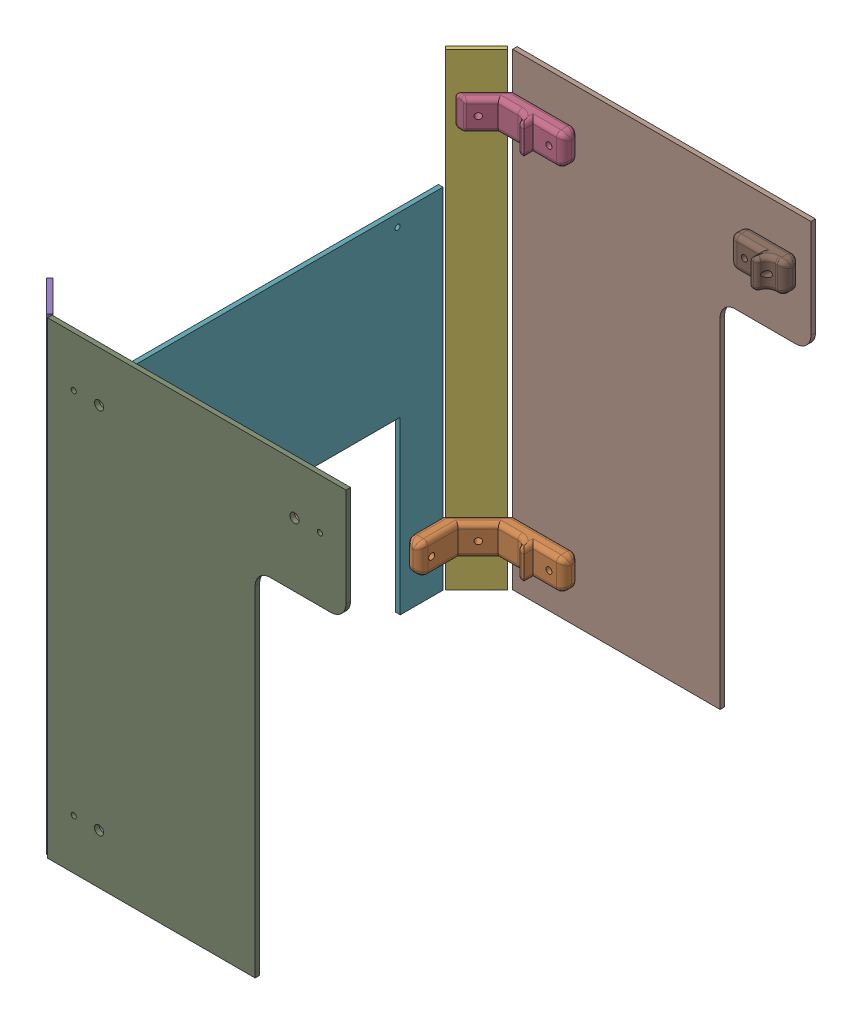
SolidWorks assembly Assemblage_Plexi, configuration Défaut. Lengths in mm.
Overall size (222.7 309 310).
11 component instances, 6 part files, 29 mates.
Components (placement in the parent):
- Support_Plexi-1: Support_Plexi [Défaut] at (-28.5354 258.1684 1538.5415) size (66.7 20 48.2)
- Support_Plexi-2: Support_Plexi [Défaut] at (-28.5354 258.1684 1254.5415) x (1 0 0) z (0 0 -1) size (66.7 20 48.2)
- Support_Plexi_2-1: Support_Plexi_2 [Défaut] at (-28.5354 501.1684 1538.5415) size (61.67 20 21)
- Support_Plexi_2-2: Support_Plexi_2 [Défaut] at (-28.5354 501.1684 1254.5415) x (1 0 0) z (0 0 -1) size (61.67 20 21)
- Plexi_Angle_V2-1: Plexi_Angle_V2 [Défaut] at (-73.2495 379.6684 1537.3274) x (0.707107 0 0.707107) z (-0.707107 0 0.707107) size (29 309 3)
- Plexi_Angle_V2-2: Plexi_Angle_V2 [Défaut] at (-76.303 379.6684 1254.5665) x (0.707107 0 -0.707107) z (0.707107 0 0.707107) size (29 309 3)
- Plexi_Arrière-1: Plexi_Arrière [Défaut] at (-85.2354 455.6484 1267.7865) x (0 0 1) z (-1 0 0) size (257.51 230.48 3)
- Plexi_Latéral-1: Plexi_Latéral [Défaut] at (35.9646 379.6684 1244.5415) x (-1 0 0) z (0 0 -1) size (197 309 3)
- Plexi_Latéral-2: Plexi_Latéral [Défaut] at (35.9646 379.6684 1551.5415) x (-1 0 0) z (0 0 -1) size (197 309 3)
- Support_Plexi_1-1: Support_Plexi_1 [Défaut] at (100.4646 501.1684 1538.5415) x (-1 0 0) z (0 0 1) size (36.75 20 16)
- Support_Plexi_1-2: Support_Plexi_1 [Défaut] at (100.4646 501.1684 1254.5415) x (-1 0 0) z (0 0 -1) size (36.75 20 16)
Mates (geometry in assembly coordinates):
- Rainure1: slot anti-aligned: cylinder of Support_Plexi-1 through (-27.7844 258.1684 1491.0905) axis (-0.707107 0 0.707107) radius 2; plane of Plexi_Angle_V2-1 through (-77.8457 256.4184 1536.9738) normal (0 1 0); cylinder of Plexi_Angle_V2-1 through (-77.8457 258.1684 1536.9738) axis (0.707107 0 -0.707107) radius 1.75
- Coïncidente1: coincident anti-aligned: plane of Support_Plexi-1 through (-62.0354 248.1684 1548.5415) normal (-0.707107 0 0.707107); plane of Plexi_Angle_V2-1 through (-73.2495 379.6684 1537.3274) normal (0.707107 0 -0.707107)
- Rainure2: slot anti-aligned: cylinder of Support_Plexi_2-1 through (-27.7844 501.1684 1491.0905) axis (-0.707107 0 0.707107) radius 2; plane of Plexi_Angle_V2-1 through (-77.8457 499.4184 1536.9738) normal (0 1 0); cylinder of Plexi_Angle_V2-1 through (-77.8457 501.1684 1536.9738) axis (0.707107 0 -0.707107) radius 1.75
- Coïncidente2: coincident anti-aligned: plane of Support_Plexi_2-1 through (-62.0354 491.1684 1548.5415) normal (-0.707107 0 0.707107); plane of Plexi_Angle_V2-1 through (-73.2495 379.6684 1537.3274) normal (0.707107 0 -0.707107)
- Coïncidente3: coincident aligned: plane of Support_Plexi-2 through (-62.0354 268.1684 1244.5415) normal (-0.707107 0 -0.707107); plane of Support_Plexi_2-2 through (-62.0354 511.1684 1244.5415) normal (-0.707107 0 -0.707107)
- Coïncidente4: coincident anti-aligned: plane of Support_Plexi-2 through (-62.0354 268.1684 1244.5415) normal (-0.707107 0 -0.707107); plane of Plexi_Angle_V2-2 through (-74.1817 379.6684 1256.6878) normal (0.707107 0 0.707107)
- Rainure3: slot aligned: plane of Plexi_Angle_V2-2 through (-76.6566 256.4184 1259.1627) normal (0 1 0); cylinder of Support_Plexi-2 through (-27.7844 258.1684 1301.9925) axis (-0.707107 0 -0.707107) radius 2; cylinder of Plexi_Angle_V2-2 through (-76.6566 258.1684 1259.1627) axis (-0.707107 0 -0.707107) radius 1.75
- Rainure5: slot aligned: cylinder of Support_Plexi_2-2 through (-27.7844 501.1684 1301.9925) axis (-0.707107 0 -0.707107) radius 2; plane of Plexi_Angle_V2-2 through (-76.6566 499.4184 1259.1627) normal (0 1 0); cylinder of Plexi_Angle_V2-2 through (-76.6566 501.1684 1259.1627) axis (-0.707107 0 -0.707107) radius 1.75
- Coïncidente5: coincident aligned: plane of Support_Plexi-1 through (-18.5354 268.1684 1541.5415) normal (0 1 0); plane of Support_Plexi-2 through (-18.5354 268.1684 1251.5415) normal (0 1 0)
- Coïncidente6: coincident aligned: plane of Support_Plexi-1 through (-85.2354 248.1684 1500.3415) normal (-1 0 0); plane of Support_Plexi-2 through (-85.2354 268.1684 1292.7415) normal (-1 0 0)
- Coaxiale1: concentric anti-aligned: cylinder of Support_Plexi-2 through (-18.5344 258.1684 1285.2415) axis (-1 0 0) radius 2; cylinder of Plexi_Arrière-1 through (-88.2354 258.1684 1285.2415) axis (1 0 0) radius 1.7
- Coaxiale2: concentric anti-aligned: cylinder of Support_Plexi-1 through (-18.5344 258.1684 1507.8415) axis (-1 0 0) radius 2; cylinder of Plexi_Arrière-1 through (-88.2354 258.1684 1507.8415) axis (1 0 0) radius 1.7
- Coïncidente7: coincident anti-aligned: plane of Support_Plexi-1 through (-85.2354 248.1684 1500.3415) normal (-1 0 0); plane of Plexi_Arrière-1 through (-85.2354 455.6484 1267.7865) normal (1 0 0)
- Coïncidente8: coincident aligned: plane of Support_Plexi-2 through (-28.5354 258.1684 1244.5415) normal (0 0 -1); plane of Support_Plexi_2-2 through (-28.5354 501.1684 1244.5415) normal (0 0 -1)
- Coïncidente9: coincident aligned: plane of Support_Plexi-1 through (-28.5354 258.1684 1548.5415) normal (0 0 1); plane of Support_Plexi_2-1 through (-28.5354 501.1684 1548.5415) normal (0 0 1)
- Parallèle1: parallel aligned: plane of Plexi_Angle_V2-1 through (-65.1178 534.1684 1549.7017) normal (0 1 0); plane of Plexi_Arrière-1 through (-88.2354 455.6484 1267.7865) normal (0 1 0)
- Parallèle2: parallel aligned: plane of Plexi_Angle_V2-2 through (-63.9286 534.1684 1246.4348) normal (0 1 0); plane of Plexi_Arrière-1 through (-88.2354 455.6484 1267.7865) normal (0 1 0)
- Coaxiale3: concentric aligned: cylinder of Support_Plexi_2-2 through (-28.5354 501.1684 1244.5415) axis (0 0 1) radius 3; cylinder of Plexi_Latéral-1 through (-28.5354 501.1684 1241.5415) axis (0 0 1) radius 3
- Coaxiale4: concentric anti-aligned: cylinder of Support_Plexi_2-2 through (-45.2854 501.1684 1292.7425) axis (0 0 -1) radius 2; cylinder of Plexi_Latéral-1 through (-45.2854 501.1684 1241.5415) axis (0 0 1) radius 1.7
- Coïncidente10: coincident anti-aligned: plane of Support_Plexi_2-2 through (-28.5354 501.1684 1244.5415) normal (0 0 -1); plane of Plexi_Latéral-1 through (35.9646 379.6684 1244.5415) normal (0 0 1)
- Coaxiale5: concentric anti-aligned: cylinder of Support_Plexi_2-1 through (-28.5354 501.1684 1548.5415) axis (0 0 -1) radius 3; cylinder of Plexi_Latéral-2 through (-28.5354 501.1684 1548.5415) axis (0 0 1) radius 3
- Coaxiale6: concentric aligned: cylinder of Support_Plexi_2-1 through (-45.2854 501.1684 1500.3405) axis (0 0 1) radius 2; cylinder of Plexi_Latéral-2 through (-45.2854 501.1684 1548.5415) axis (0 0 1) radius 1.7
- Coïncidente11: coincident anti-aligned: plane of Support_Plexi_2-1 through (-28.5354 501.1684 1548.5415) normal (0 0 1); plane of Plexi_Latéral-2 through (35.9646 379.6684 1548.5415) normal (0 0 -1)
- Coïncidente12: coincident aligned: plane of Support_Plexi_1-1 through (107.2146 491.1684 1541.5415) normal (0 -1 0); plane of Support_Plexi_1-2 through (90.4646 491.1684 1251.5415) normal (0 -1 0)
- Coïncidente14: coincident anti-aligned: plane of Plexi_Latéral-2 through (35.9646 379.6684 1548.5415) normal (0 0 -1); plane of Support_Plexi_1-1 through (117.2146 501.1684 1548.5415) normal (0 0 1)
- Coaxiale7: concentric anti-aligned: cylinder of Support_Plexi_1-1 through (100.4646 501.1684 1548.5415) axis (0 0 -1) radius 3; cylinder of Plexi_Latéral-2 through (100.4646 501.1684 1548.5415) axis (0 0 1) radius 3
- Coïncidente15: coincident anti-aligned: plane of Plexi_Latéral-1 through (35.9646 379.6684 1244.5415) normal (0 0 1); plane of Support_Plexi_1-2 through (100.4646 501.1684 1244.5415) normal (0 0 -1)
- Coaxiale8: concentric anti-aligned: cylinder of Support_Plexi_1-2 through (117.2146 501.1684 1292.7425) axis (0 0 -1) radius 2; cylinder of Plexi_Latéral-1 through (117.2146 501.1684 1241.5415) axis (0 0 1) radius 1.7
- Coïncidente16: coincident aligned: plane of Support_Plexi_2-1 through (-18.5354 511.1684 1541.5415) normal (0 1 0); plane of Support_Plexi_1-1 through (107.2146 511.1684 1541.5415) normal (0 1 0)
